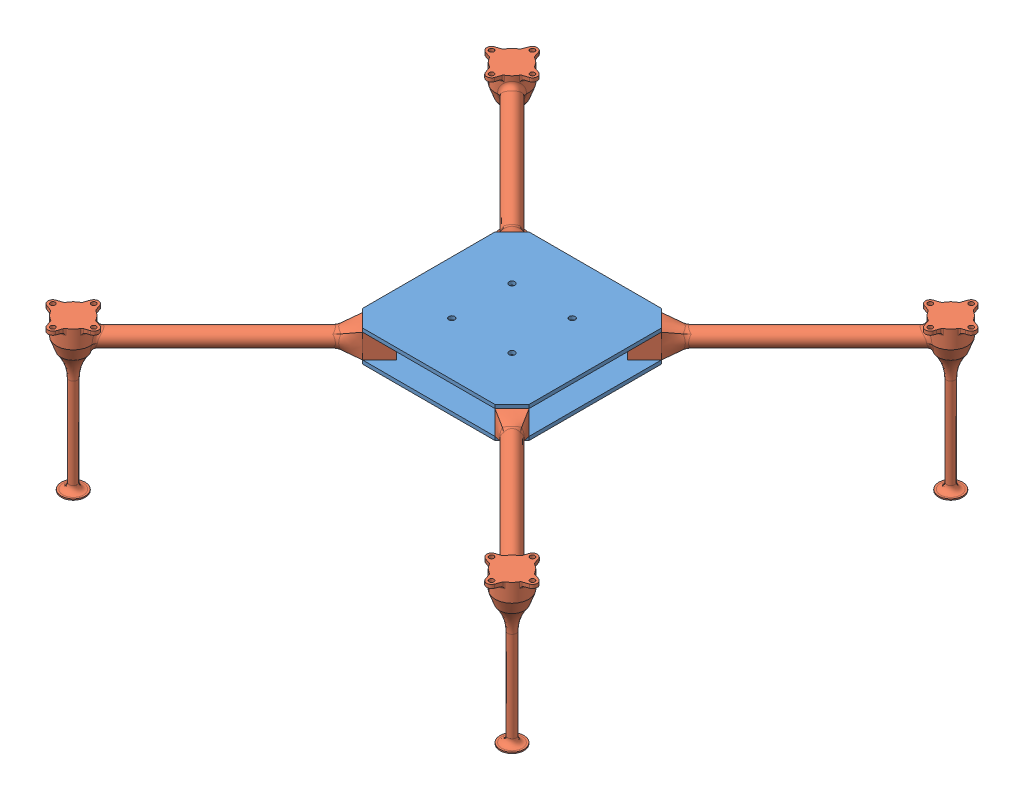
SolidWorks assembly Assem3, configuration Default. Lengths in mm.
Overall size (409.87 126 409.87).
6 component instances, 2 part files, 15 mates.
Components (placement in the parent):
- base_plate-1: base_plate [Default] at (50.4172 67.9872 109.6164) size (138.28 3 138.28)
- arm_2-1: arm_2 [Default] at (-11.6539 80.9872 171.6875) x (0 1 0) z (0.707107 0 0.707107) size (126 206.02 32.04)
- arm_2-2: arm_2 [Default] at (112.4883 80.9872 171.6875) x (0 1 0) z (0.707107 0 -0.707107) size (126 206.02 32.04)
- arm_2-3: arm_2 [Default] at (112.4883 80.9872 47.5454) x (0 1 0) z (-0.707107 0 -0.707107) size (126 206.02 32.04)
- arm_2-4: arm_2 [Default] at (-11.6539 80.9872 47.5454) x (0 1 0) z (-0.707107 0 0.707107) size (126 206.02 32.04)
- base_plate-2: base_plate [Default] at (50.4172 90.9872 109.6164) size (138.28 3 138.28)
Mates (geometry in assembly coordinates):
- Coincident1: coincident: point of base_plate-1; point of arm_2-2
- Coincident2: coincident: point of base_plate-1; point of arm_2-2
- Coincident3: coincident: point of base_plate-1; point of arm_2-3
- Coincident4: coincident: point of base_plate-1; point of arm_2-3
- Coincident5: coincident: point of base_plate-1; point of arm_2-4
- Coincident6: coincident: point of base_plate-1; point of arm_2-4
- Coincident7: coincident: point of base_plate-1; point of arm_2-1
- Coincident8: coincident: point of base_plate-1; point of arm_2-1
- Coincident9: coincident anti-aligned: plane of base_plate-1 through (50.4172 70.9872 109.6164) normal (0 1 0); plane of arm_2-1 through (-4.5828 70.9872 150.4743) normal (0 -1 0)
- Coincident10: coincident anti-aligned: plane of base_plate-1 through (50.4172 70.9872 109.6164) normal (0 1 0); plane of arm_2-2 through (91.2751 70.9872 164.6164) normal (0 -1 0)
- Coincident11: coincident anti-aligned: plane of base_plate-1 through (50.4172 70.9872 109.6164) normal (0 1 0); plane of arm_2-4 through (9.5593 70.9872 54.6164) normal (0 -1 0)
- Coincident12: coincident anti-aligned: plane of base_plate-1 through (50.4172 70.9872 109.6164) normal (0 1 0); plane of arm_2-3 through (105.4172 70.9872 68.7586) normal (0 -1 0)
- Coincident13: coincident: point of arm_2-3; point of base_plate-2
- Coincident14: coincident: point of arm_2-3; point of base_plate-2
- Coincident15: coincident: point of arm_2-2; point of base_plate-2
